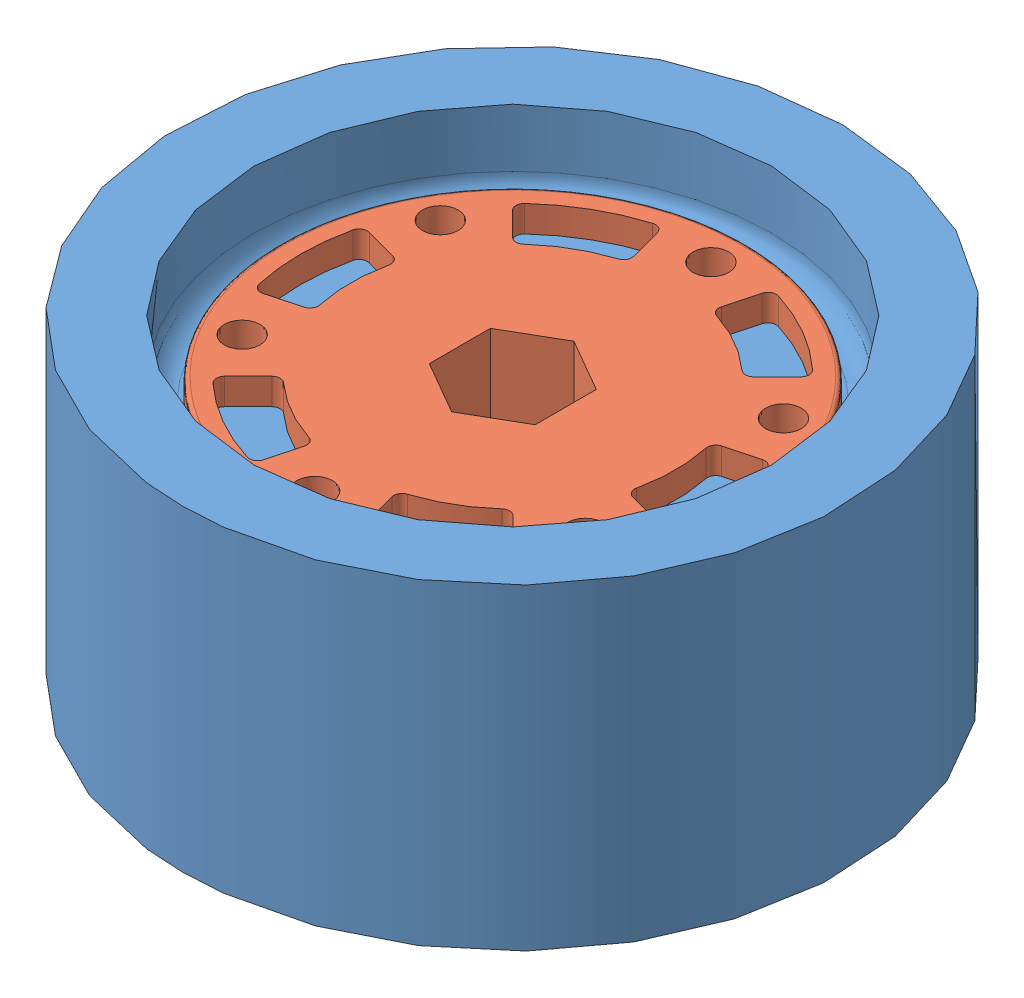
SolidWorks assembly Weight Assembly, configuration Default. Lengths in mm.
Overall size (79.38 38.1 79.38).
3 component instances, 2 part files, 6 mates.
Components (placement in the parent):
- T23 - Flywheel weight-1: T23 - Flywheel weight [Default] at (38.4323 36.9974 59.2877) size (79.38 38.1 79.38)
- 1_2_Hex_Bore_Aluminum_VersaHub_217-2592-1: 1_2_Hex_Bore_Aluminum_VersaHub_217-2592 [Default] at (38.4323 36.9974 59.2877) x (0 1 0) z (0.5 0 0.866025) size (12.7 55.88 55.88)
- 1_2_Hex_Bore_Aluminum_VersaHub_217-2592-2: 1_2_Hex_Bore_Aluminum_VersaHub_217-2592 [Default] at (38.4323 36.9974 59.2877) x (0 -1 0) z (-0.5 0 0.866025) size (12.7 55.88 55.88)
Mates (geometry in assembly coordinates):
- Coincident1: coincident: plane of Weight-1 through (38.4323 46.5224 59.2877) normal (0 1 0); plane of 1_2_Hex_Bore_Aluminum_VersaHub_217-2592-1 through (26.0526 46.5224 66.4351) normal (0 -1 0)
- Concentric1: concentric: cylinder of Weight-1 through (17.8101 46.5224 71.1939) axis (0 1 0) radius 2.4892; cylinder of 1_2_Hex_Bore_Aluminum_VersaHub_217-2592-1 through (17.8101 -36.096 71.1939) axis (0 1 0) radius 2.15
- Concentric2: concentric aligned: cylinder of Weight-1 through (38.4323 46.5224 35.4752) axis (0 1 0) radius 2.4892; cylinder of 1_2_Hex_Bore_Aluminum_VersaHub_217-2592-1 through (38.4323 -36.096 35.4752) axis (0 1 0) radius 2.15
- Coincident2: coincident: plane of Weight-1 through (38.4323 27.4724 59.2877) normal (0 -1 0); plane of 1_2_Hex_Bore_Aluminum_VersaHub_217-2592-2 through (50.8121 27.4724 66.4351) normal (0 1 0)
- Concentric3: concentric: cylinder of Weight-1 through (59.0546 46.5224 47.3814) axis (0 1 0) radius 2.4892; cylinder of 1_2_Hex_Bore_Aluminum_VersaHub_217-2592-2 through (59.0546 110.0907 47.3814) axis (0 -1 0) radius 2.15
- Concentric4: concentric anti-aligned: cylinder of Weight-1 through (38.4323 46.5224 35.4752) axis (0 1 0) radius 2.4892; cylinder of 1_2_Hex_Bore_Aluminum_VersaHub_217-2592-2 through (38.4323 110.0907 35.4752) axis (0 -1 0) radius 2.15
